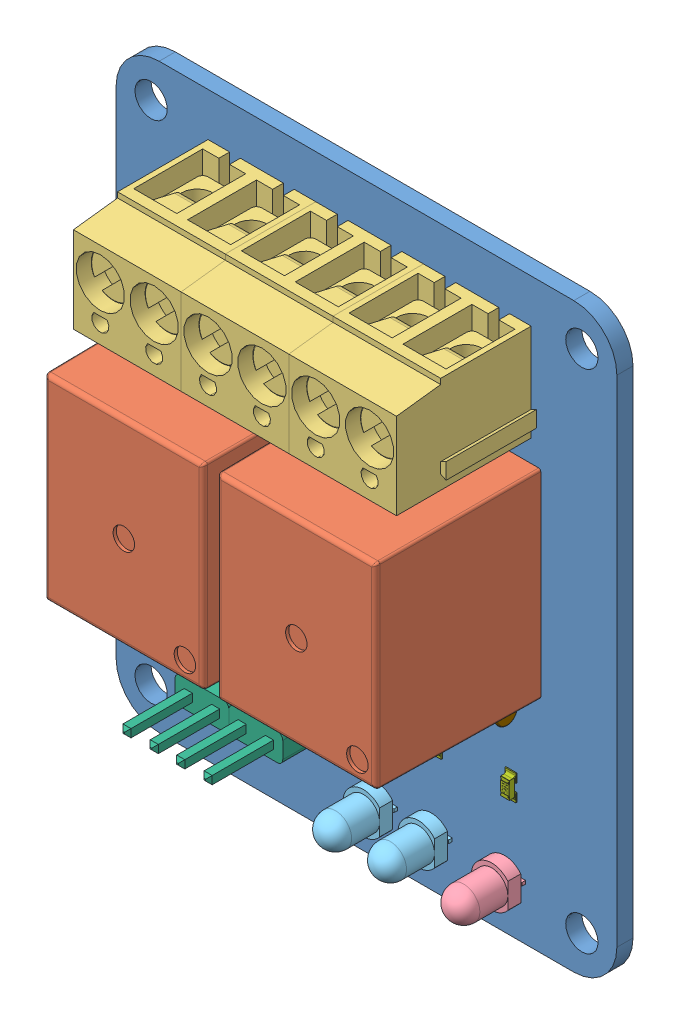
SolidWorks assembly Carte 2 relais, configuration Défaut. Lengths in mm.
Overall size (46.5 54 18.45).
20 component instances, 9 part files, 35 mates.
Components (placement in the parent):
- circuit imprimé-1: circuit imprimé [Défaut] at origin size (46.5 54 1.5)
- relais 10A 250VAC-1: relais 10A 250VAC [Défaut] at (15.9188 29.6633 1.5) x (0 -1 0) z (0 0 1) size (18.5 15 17.2)
- relais 10A 250VAC-2: relais 10A 250VAC [Défaut] at (31.9347 29.6633 1.5) x (0 -1 0) z (0 0 1) size (18.5 15 17.2)
- Bornier 2x-1: Bornier 2x [По умолчанию] at (17.9179 42.0569 2.2888) x (-1 0 0) z (0 1 0) size (10.5 12.5 9)
- Bornier 2x-2: Bornier 2x [По умолчанию] at (7.9179 42.0569 2.2888) x (-1 0 0) z (0 1 0) size (10.5 12.5 9)
- Bornier 2x-3: Bornier 2x [По умолчанию] at (27.9179 42.0569 2.2888) x (-1 0 0) z (0 1 0) size (10.5 12.5 9)
- 3mm LED verte-1: 3mm LED verte [Default] at (36.7892 4.9861 2.2141) x (1 0 0) z (0 -1 0) size (3.4 8.01 3.8)
- 3mm LED rouge-1: 3mm LED rouge [Default] at (24.8839 4.9351 2.2141) x (1 0 0) z (0 -1 0) size (3.4 8.01 3.8)
- 3mm LED rouge-2: 3mm LED rouge [Default] at (29.9823 4.9988 2.2141) x (1 0 0) z (0 -1 0) size (3.4 8.01 3.8)
- 2pin_header-1: 2pin_header [Default] at (10.4764 6.8482 1.5) x (1 0 0) z (0 -1 0) size (5 11.75 2.54)
- 2pin_header-2: 2pin_header [Default] at (15.4764 6.8482 1.5) x (1 0 0) z (0 -1 0) size (5 11.75 2.54)
- 603 resistor-1: 603 resistor [Default] at (14.7669 12.3438 1.5) x (0 -1 0) z (-1 0 0) size (2.36 0.61 1.03)
- 603 resistor-2: 603 resistor [Default] at (29.7778 12.2189 1.5) x (0 -1 0) z (-1 0 0) size (2.36 0.61 1.03)
- 603 resistor-3: 603 resistor [Default] at (36.7083 12.194 1.5) x (0 -1 0) z (-1 0 0) size (2.36 0.61 1.03)
- 603 resistor-4: 603 resistor [Default] at (11.2738 12.3199 1.5) x (0 -1 0) z (-1 0 0) size (2.36 0.61 1.03)
- 603 resistor-5: 603 resistor [Default] at (24.7621 12.1382 1.5) x (0 -1 0) z (-1 0 0) size (2.36 0.61 1.03)
- TO92-1: TO92 [Default] at (12.2317 18.082 4) x (1 0 0) z (0 -1 0) size (5.53 9.3 4.1)
- TO92-2: TO92 [Default] at (28.4884 18.1004 4) x (1 0 0) z (0 -1 0) size (5.53 9.3 4.1)
- diode zener-1: diode zener [Défaut] at (35.329 18.6616 2.5) x (0.999951 0.009863 -0.000034) z (0.000033 0.000069 1) size (3.5 2 2)
- diode zener-2: diode zener [Défaut] at (19.3202 18.7389 2.5) x (0.999959 0.009107 -0.000021) z (0.00002 0.00006 1) size (3.5 2 2)
Mates (geometry in assembly coordinates):
- Coïncidente1: coincident: plane of relais 10A 250VAC-1 through (15.9188 29.6633 1.5) normal (0 0 -1); plane of circuit imprimé-1 through (4 4 1.5) normal (0 0 1)
- Parallèle2: parallel: plane of relais 10A 250VAC-1 through (8.4188 38.9133 1.5) normal (-0.999962 0 0.008727); line of circuit imprimé-1 through (0 50 0) axis (0 -1 0)
- Coïncidente3: coincident anti-aligned: plane of circuit imprimé-1 through (4 4 1.5) normal (0 0 1); plane of relais 10A 250VAC-2 through (31.9347 29.6633 1.5) normal (0 0 -1)
- Parallèle3: parallel: line of circuit imprimé-1 through (0 50 0) axis (0 -1 0); plane of relais 10A 250VAC-2 through (24.4347 38.9133 1.5) normal (-0.999962 0 0.008727)
- Coïncidente5: coincident aligned: plane of relais 10A 250VAC-1 through (8.4188 20.4133 1.5) normal (0 -0.999962 0.008727); plane of relais 10A 250VAC-2 through (24.4347 20.4133 1.5) normal (0 -0.999962 0.008727)
- Coïncidente6: coincident anti-aligned: plane of circuit imprimé-1 through (4 4 1.5) normal (0 0 1); plane of Bornier 2x-3 through (38.5383 49.9667 1.5) normal (0 0 -1)
- Coïncidente7: coincident anti-aligned: plane of circuit imprimé-1 through (4 4 1.5) normal (0 0 1); plane of Bornier 2x-1 through (28.5383 49.9667 1.5) normal (0 0 -1)
- Coïncidente8: coincident anti-aligned: plane of circuit imprimé-1 through (4 4 1.5) normal (0 0 1); plane of Bornier 2x-2 through (18.5383 49.9667 1.5) normal (0 0 -1)
- Parallèle4: parallel aligned: plane of circuit imprimé-1 through (4 54 1.5) normal (0 1 0); plane of Bornier 2x-2 through (18.5383 49.9667 1.5) normal (0 1 0)
- Coïncidente11: coincident aligned: plane of Bornier 2x-1 through (28.5383 49.9667 1.5) normal (0 1 0); plane of Bornier 2x-2 through (18.5383 49.9667 1.5) normal (0 1 0)
- Coïncidente12: coincident aligned: plane of Bornier 2x-1 through (28.5383 49.9667 1.5) normal (0 1 0); plane of Bornier 2x-3 through (38.5383 49.9667 1.5) normal (0 1 0)
- Coïncidente13: coincident anti-aligned: plane of Bornier 2x-1 through (18.5383 49.9667 14) normal (-1 0 0); plane of Bornier 2x-2 through (18.5383 49.9667 14) normal (1 0 0)
- Coïncidente14: coincident anti-aligned: plane of Bornier 2x-1 through (28.5383 49.9667 14) normal (1 0 0); plane of Bornier 2x-3 through (28.5383 49.9667 14) normal (-1 0 0)
- Coïncidente15: coincident anti-aligned: plane of circuit imprimé-1 through (4 4 1.5) normal (0 0 1); plane of 3mm LED rouge-2 through (30.4463 5.9795 1.5) normal (0 0 -1)
- Coïncidente16: coincident anti-aligned: plane of circuit imprimé-1 through (4 4 1.5) normal (0 0 1); plane of 3mm LED rouge-1 through (25.348 5.9158 1.5) normal (0 0 -1)
- Coïncidente17: coincident anti-aligned: plane of circuit imprimé-1 through (4 4 1.5) normal (0 0 1); plane of 3mm LED verte-1 through (37.2532 5.9668 1.5) normal (0 0 -1)
- Coïncidente18: coincident anti-aligned: plane of circuit imprimé-1 through (4 4 1.5) normal (0 0 1); plane of 2pin_header-1 through (12.4764 6.0782 1.5) normal (0 0 -1)
- Coïncidente19: coincident anti-aligned: plane of circuit imprimé-1 through (4 4 1.5) normal (0 0 1); plane of 2pin_header-2 through (17.4764 6.0782 1.5) normal (0 0 -1)
- Coïncidente20: coincident aligned: plane of 2pin_header-1 through (12.4764 5.5782 4) normal (0 -1 0); plane of 2pin_header-2 through (17.4764 5.5782 4) normal (0 -1 0)
- Coïncidente21: coincident anti-aligned: plane of 2pin_header-1 through (12.9764 7.6182 4) normal (1 0 0); plane of 2pin_header-2 through (12.9764 6.0782 4) normal (-1 0 0)
- Coïncidente22: coincident anti-aligned: plane of circuit imprimé-1 through (4 4 1.5) normal (0 0 1); plane of 603 resistor-1 through (14.7669 12.3438 1.5) normal (0 0 -1)
- Coïncidente23: coincident anti-aligned: plane of circuit imprimé-1 through (4 4 1.5) normal (0 0 1); plane of 603 resistor-4 through (11.2738 12.3199 1.5) normal (0 0 -1)
- Coïncidente24: coincident anti-aligned: plane of circuit imprimé-1 through (4 4 1.5) normal (0 0 1); plane of 603 resistor-2 through (29.7778 12.2189 1.5) normal (0 0 -1)
- Coïncidente25: coincident anti-aligned: plane of circuit imprimé-1 through (4 4 1.5) normal (0 0 1); plane of 603 resistor-3 through (36.7083 12.194 1.5) normal (0 0 -1)
- Coïncidente26: coincident anti-aligned: plane of circuit imprimé-1 through (4 4 1.5) normal (0 0 1); plane of 603 resistor-5 through (24.7621 12.1382 1.5) normal (0 0 -1)
- Parallèle6: parallel aligned: plane of circuit imprimé-1 through (0 4 1.5) normal (-1 0 0); plane of 603 resistor-4 through (10.8738 11.5449 2.075) normal (-1 0 0)
- Parallèle7: parallel aligned: plane of circuit imprimé-1 through (0 4 1.5) normal (-1 0 0); plane of 603 resistor-2 through (29.3778 11.4439 2.075) normal (-1 0 0)
- Parallèle8: parallel aligned: plane of circuit imprimé-1 through (0 4 1.5) normal (-1 0 0); plane of 603 resistor-3 through (36.3083 11.419 2.075) normal (-1 0 0)
- Parallèle9: parallel aligned: plane of circuit imprimé-1 through (0 4 1.5) normal (-1 0 0); plane of 603 resistor-5 through (24.3621 11.3632 2.075) normal (-1 0 0)
- Parallèle10: parallel aligned: plane of circuit imprimé-1 through (0 4 1.5) normal (-1 0 0); plane of 603 resistor-1 through (14.3669 11.5688 2.075) normal (-1 0 0)
- Distance1: distance = 2.5 mm anti-aligned: plane of TO92-1 through (12.2317 18.082 4) normal (0 0 -1); plane of circuit imprimé-1 through (4 4 1.5) normal (0 0 1)
- Distance2: distance = 2.5 mm anti-aligned: plane of circuit imprimé-1 through (4 4 1.5) normal (0 0 1); plane of TO92-2 through (28.4884 18.1004 4) normal (0 0 -1)
- Tangent1: tangent: plane of circuit imprimé-1 through (4 4 1.5) normal (0 0 1); face of diode zener-1
- Tangent2: tangent: plane of circuit imprimé-1 through (4 4 1.5) normal (0 0 1); face of diode zener-1
- Tangent3: tangent: plane of circuit imprimé-1 through (4 4 1.5) normal (0 0 1); face of diode zener-2
